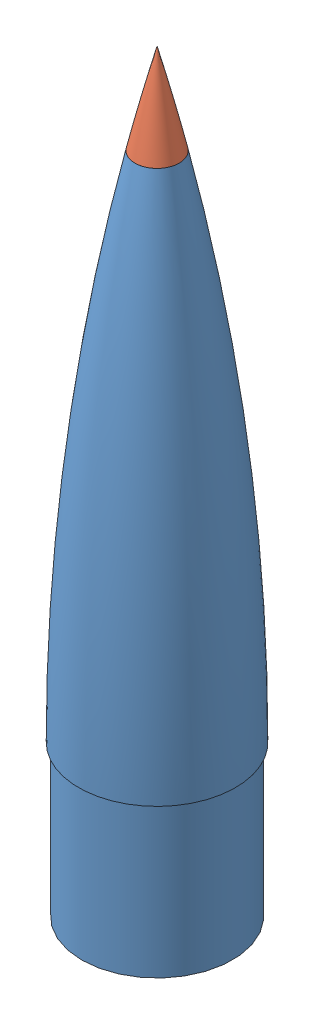
SolidWorks assembly nosecone, configuration Default. Lengths in mm.
Overall size (132.08 635 132.08).
2 component instances, 2 part files, 2 mates.
Components (placement in the parent):
- nosecone_shell-1: nosecone_shell [Default] at (132.5114 123.8831 521.6176) size (132.08 558.8 132.08)
- nosecone_tip-1: nosecone_tip [Default] at (132.5114 555.6831 521.6176) size (37.1 76.2 37.1)
Mates (geometry in assembly coordinates):
- Coincident1: coincident aligned: circle of nosecone_shell-1; plane of nosecone_tip-1 through (132.5114 555.6831 521.6176) normal (0 -1 0)
- Coincident2: coincident aligned: line of nosecone_shell-1 through (132.5114 123.8831 521.6176) axis (0 -1 0); line of nosecone_tip-1 through (132.5114 631.8831 521.6176) axis (0 -1 0)
